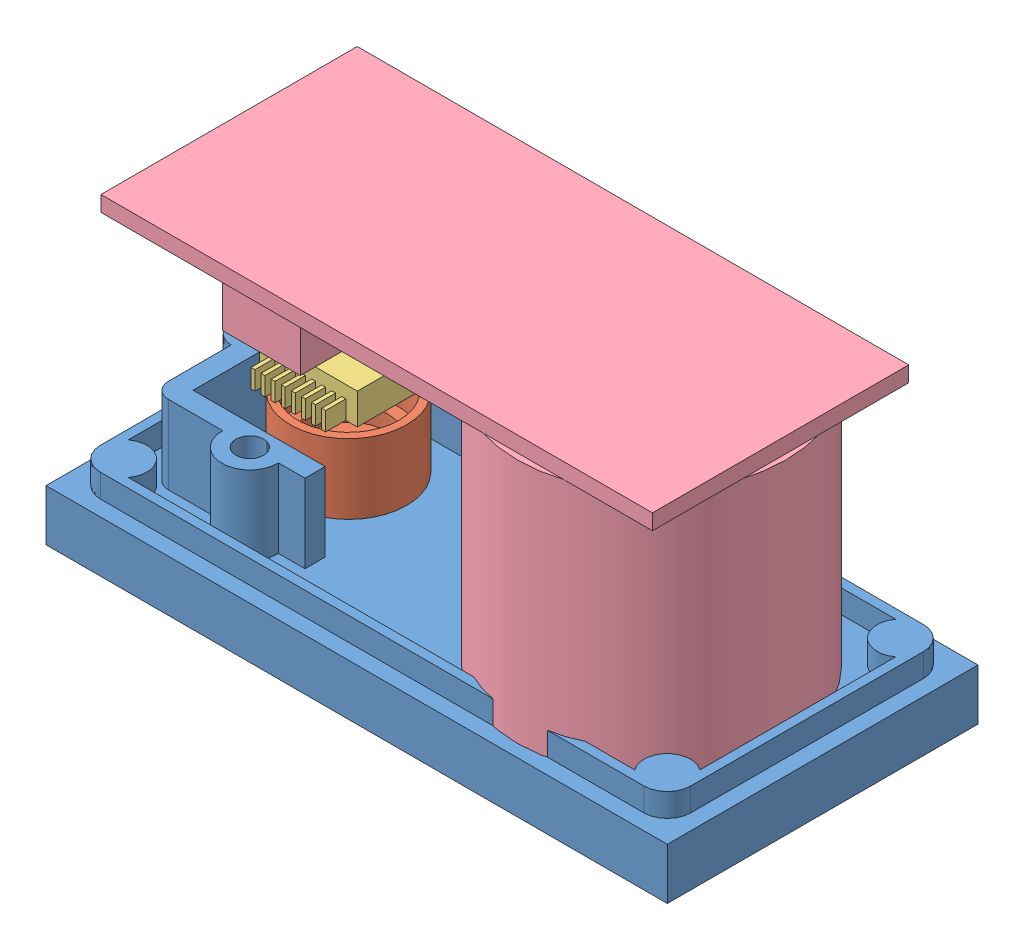
SolidWorks assembly assy, configuration Default. Lengths in mm.
Overall size (40 26.3 20).
5 component instances, 5 part files, 9 mates.
Components (placement in the parent):
- vaihteiston pohja-1: vaihteiston pohja [Default] at (-18.7559 -8.3087 12.7056) size (40 8.35 20)
- magneettipidin-1: magneettipidin [Default] at (-29.2847 -4.5087 12.7056) x (-0.837169 0 -0.546944) z (-0.546944 0 0.837169) size (7.5 14.5 7.5)
- as5045-1: as5045 [Default] at (-29.2994 0.8413 12.6184) x (-1 0 0) z (0 0 -1) size (6.3 2 7.9)
- kuori-1: kuori [Default] at (-18.8559 2.0913 12.8056) size (40.2 14.2 20.2) (hidden)
- levy-1: levy [Default] at (-18.6669 11.7913 13.2556) x (-1 0 0) z (0 0 1) size (35.85 19.6 17.3)
Mates (geometry in assembly coordinates):
- Distance1: distance = 0.5 mm anti-aligned: plane of magneettipidin-1 through (-29.2847 -4.5087 12.7056) normal (0 -1 0); plane of vaihteiston pohja-1 through (-38.7559 -5.0087 2.7056) normal (0 1 0)
- Concentric1: concentric aligned: cylinder of vaihteiston pohja-1 through (-29.2847 -7.0087 12.7056) axis (0 1 0) radius 2.45; cylinder of magneettipidin-1 through (-29.2847 -14.5087 12.7056) axis (0 1 0) radius 1.75
- Parallel1: parallel anti-aligned: plane of vaihteiston pohja-1 through (-34.2847 0.0413 17.7056) normal (1 0 0); plane of as5045-1 through (-32.4494 2.8413 15.2684) normal (-1 0 0)
- Distance3: distance = 0.8 mm anti-aligned: plane of as5045-1 through (-26.1494 0.8413 9.9684) normal (0 -1 0); plane of vaihteiston pohja-1 through (-29.2847 0.0413 6.3556) normal (0 1 0)
- Coincident2: coincident anti-aligned: plane of vaihteiston pohja-1 through (-38.7559 -5.0087 2.7056) normal (0 1 0); plane of kuori-1 through (-38.9559 -5.0087 2.7056) normal (0 -1 0)
- Coincident3: coincident aligned: plane of vaihteiston pohja-1 through (1.2441 -5.0087 22.7056) normal (1 0 0); plane of kuori-1 through (1.2441 -5.0087 22.9056) normal (1 0 0)
- Coincident4: coincident aligned: plane of vaihteiston pohja-1 through (-38.7559 -5.0087 2.7056) normal (0 0 -1); plane of kuori-1 through (-38.9559 -5.0087 2.7056) normal (0 0 -1)
- Distance4: distance = 15.8 mm aligned: plane of levy-1 through (-0.9169 10.7913 21.5056) normal (0 -1 0); plane of kuori-1 through (-38.9559 -5.0087 2.7056) normal (0 -1 0)
- Distance5: distance = 1.5 mm anti-aligned: plane of levy-1 through (-0.9169 10.7913 5.0056) normal (0 0 -1); plane of kuori-1 through (0.4441 7.9413 3.5056) normal (0 0 1)
